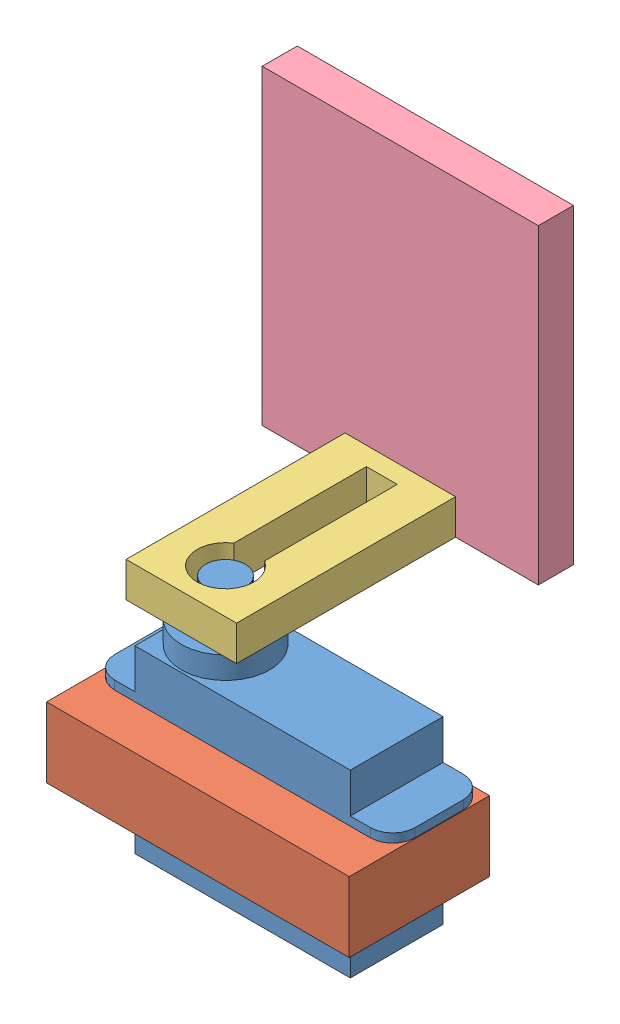
SolidWorks assembly Servo and Mounts, configuration Default. Lengths in mm.
Overall size (31.9 47.47 29.55).
4 component instances, 4 part files, 6 mates.
Components (placement in the parent):
- Servo PowerHD DSP33-1: Servo PowerHD DSP33 [Default] at (10.3442 32.3124 38.838) size (27.17 21.7 8.4)
- Servo Mounts-1: Servo Mounts [Default] at (10.3442 37.8624 38.838) size (27.4 6.35 15.05)
- Servo Cap Mount-1: Servo Cap Mount [Default] at (9.3442 51.6124 38.638) size (10 3.17 23)
- Mirror Mount-1: Mirror Mount [Default] at (1.8442 79.7874 18.813) x (1 0 0) z (0 1 0) size (25 3.17 28.17)
Mates (geometry in assembly coordinates):
- Coincident5: coincident: point of Servo PowerHD DSP33-1; point of Servo Mounts-1
- Concentric1: concentric aligned: circle of Servo PowerHD DSP33-1; cylinder of Servo Cap Mount-1 through (14.3442 51.6114 34.638) axis (0 1 0) radius 2.565
- Distance1: distance = 1 mm anti-aligned: plane of Servo PowerHD DSP33-1 through (14.3442 50.6124 34.638) normal (0 1 0); plane of Servo Cap Mount-1 through (9.3442 51.6124 38.638) normal (0 -1 0)
- Coincident10: coincident: point of Servo Cap Mount-1; point of Mirror Mount-1
- Coincident11: coincident: point of Servo Cap Mount-1; point of Mirror Mount-1
- Coincident12: coincident: line of Servo Cap Mount-1 through (17.3442 51.6124 18.813) axis (-1 0 0); plane of Mirror Mount-1 through (1.8442 79.7874 18.813) normal (0 0 1)
